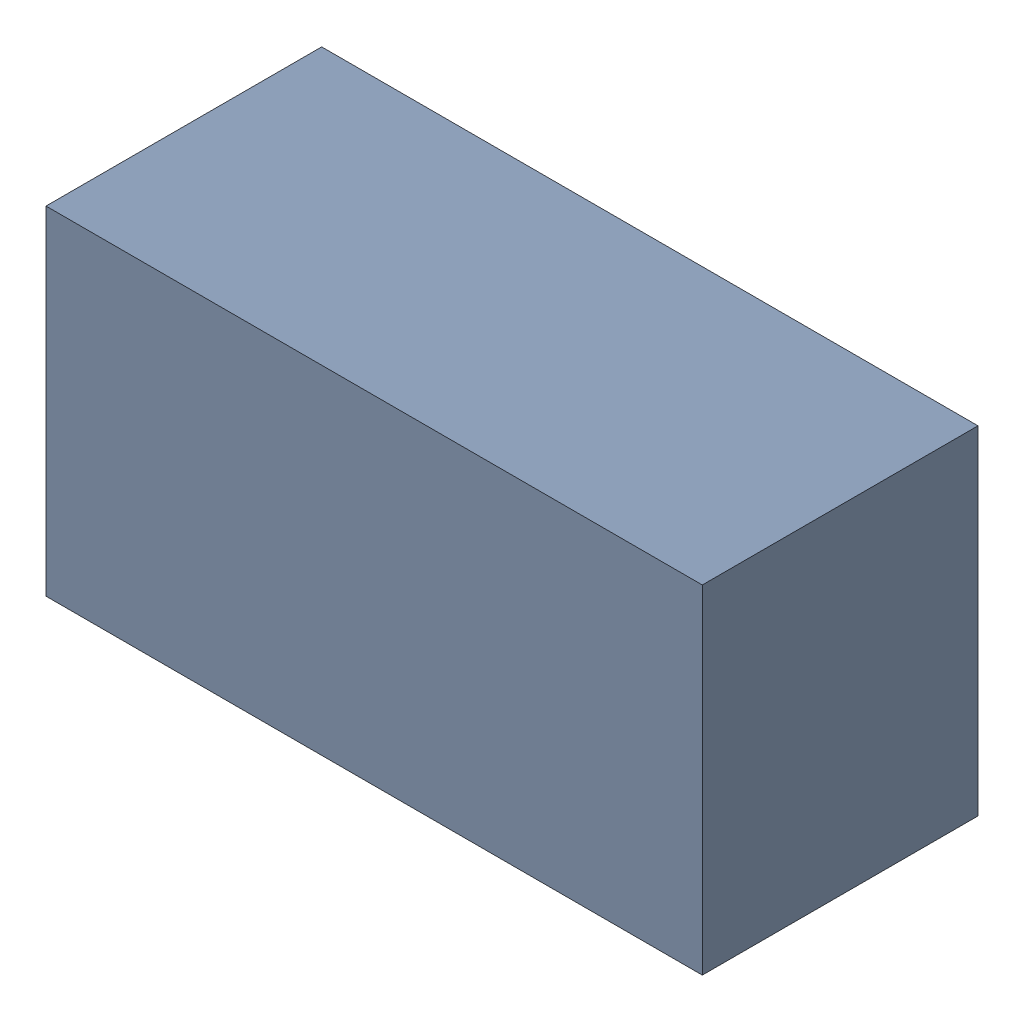
SolidWorks assembly FB1.step, configuration Default. Lengths in mm.
Overall size (33.02 17 13.87).
5 component instances, 3 part files, 0 mates.
Components (placement in the parent):
- FBead_Murata_BLM18EG221SN1D_eec.step-1: FBead_Murata_BLM18EG221SN1D_eec.step [Default] at (25.61 65.924 0) x (0 1 0) z (0 0 1) size (17 33.02 13.87)
  - Body.step-1: Body.step [Default] x (-1 0 0) z (0 0 1) size (17 33.02 13.87)
  - side.step-1: side.step [Default] at (-0.5 0.4917 0) x (-1 0 0) z (0 0 1) size (0.4 0.8 0.95)
  - side.step-2: side.step [Default] at (0.5 0.4917 0.95) x (1 0 0) z (0 0 -1) size (0.4 0.8 0.95)
  - Murata.step-1: Murata.step [Default] at (-0.8876 -0.696 0.892) size (0.61 0.14 0.03)
